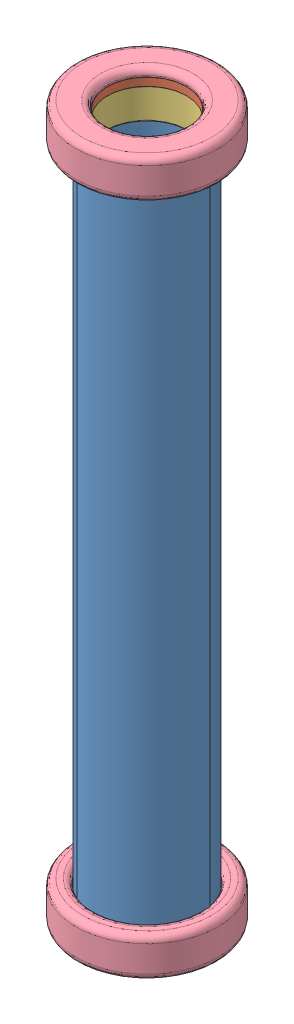
SolidWorks assembly Ftx_GeneratriceNavette, configuration Défaut. Lengths in mm.
Overall size (75.15 271 75.15).
16 component instances, 4 part files, 30 mates.
Components (placement in the parent):
- Ftx_NavetteTube-1: Ftx_NavetteTube [Défaut] at (-23.9862 -106.4594 0) size (40 265 40)
- Ftx_NavetteBague-1: Ftx_NavetteBague [Défaut] at (-23.9862 155.5406 0) size (37.5 3 37.5)
- Ftx_NavetteBague-2: Ftx_NavetteBague [Défaut] at (-23.9862 -103.4594 0) x (0.837169 0 0.546944) z (0.546944 0 -0.837169) size (37.5 3 37.5)
- Ftx_NavetteAimant-1: Ftx_NavetteAimant [Défaut] at (-23.9862 143.5406 0) size (37.5 12 37.5)
- Ftx_NavetteAimant-2: Ftx_NavetteAimant [Défaut] at (-23.9862 118.8406 0) size (37.5 12 37.5)
- Ftx_NavetteAimant-3: Ftx_NavetteAimant [Défaut] at (-23.9862 94.1406 0) size (37.5 12 37.5)
- Ftx_NavetteAimant-4: Ftx_NavetteAimant [Défaut] at (-23.9862 69.4406 0) size (37.5 12 37.5)
- Ftx_NavetteAimant-5: Ftx_NavetteAimant [Défaut] at (-23.9862 44.7406 0) size (37.5 12 37.5)
- Ftx_NavetteAimant-6: Ftx_NavetteAimant [Défaut] at (-23.9862 20.0406 0) size (37.5 12 37.5)
- Ftx_NavetteAimant-7: Ftx_NavetteAimant [Défaut] at (-23.9862 -4.6594 0) size (37.5 12 37.5)
- Ftx_NavetteAimant-8: Ftx_NavetteAimant [Défaut] at (-23.9862 -29.3594 0) size (37.5 12 37.5)
- Ftx_NavetteAimant-9: Ftx_NavetteAimant [Défaut] at (-23.9862 -54.0594 0) size (37.5 12 37.5)
- Ftx_NavetteAimant-10: Ftx_NavetteAimant [Défaut] at (-23.9862 -78.7594 0) size (37.5 12 37.5)
- Ftx_NavetteAimant-11: Ftx_NavetteAimant [Défaut] at (-23.9862 -103.4594 0) size (37.5 12 37.5)
- Ftx_NavetteButee-1: Ftx_NavetteButee [Défaut] at (-23.9862 -109.4594 0) x (0.926681 0 -0.37585) z (0.37585 0 0.926681) size (54 15 54)
- Ftx_NavetteButee-2: Ftx_NavetteButee [Défaut] at (-23.9862 161.5406 0) x (0.57022 0 0.821492) z (0.821492 0 -0.57022) size (54 15 54)
Mates (geometry in assembly coordinates):
- Coaxiale1: concentric aligned: circle of Ftx_NavetteTube-1; circle of Ftx_NavetteBague-1
- Coïncidente1: coincident aligned: plane of Ftx_NavetteTube-1 through (-23.9862 158.5406 0) normal (0 1 0); plane of Ftx_NavetteBague-1 through (-23.9862 158.5406 0) normal (0 1 0)
- Coaxiale2: concentric anti-aligned: circle of Ftx_NavetteTube-1; circle of Ftx_NavetteBague-2
- Coïncidente2: coincident aligned: plane of Ftx_NavetteTube-1 through (-23.9862 -106.4594 0) normal (0 -1 0); plane of Ftx_NavetteBague-2 through (-23.9862 -106.4594 0) normal (0 -1 0)
- Coaxiale3: concentric aligned: cylinder of Ftx_NavetteTube-1 through (-23.9862 158.5406 0) axis (0 -1 0) radius 19; cylinder of Ftx_NavetteAimant-1 through (-23.9862 155.5406 0) axis (0 -1 0) radius 18.75
- Coïncidente3: coincident anti-aligned: plane of Ftx_NavetteBague-1 through (-23.9862 155.5406 0) normal (0 -1 0); plane of Ftx_NavetteAimant-1 through (-23.9862 155.5406 0) normal (0 1 0)
- Coaxiale4: concentric aligned: cylinder of Ftx_NavetteTube-1 through (-23.9862 158.5406 0) axis (0 -1 0) radius 19; cylinder of Ftx_NavetteAimant-2 through (-23.9862 130.8406 0) axis (0 -1 0) radius 18.75
- Distance1: distance = 12.7 mm anti-aligned: plane of Ftx_NavetteAimant-2 through (-23.9862 130.8406 0) normal (0 1 0); plane of Ftx_NavetteAimant-1 through (-23.9862 143.5406 0) normal (0 -1 0)
- Coaxiale5: concentric aligned: cylinder of Ftx_NavetteTube-1 through (-23.9862 158.5406 0) axis (0 -1 0) radius 19; cylinder of Ftx_NavetteAimant-3 through (-23.9862 106.1406 0) axis (0 -1 0) radius 18.75
- Distance2: distance = 12.7 mm anti-aligned: plane of Ftx_NavetteAimant-3 through (-23.9862 106.1406 0) normal (0 1 0); plane of Ftx_NavetteAimant-2 through (-23.9862 118.8406 0) normal (0 -1 0)
- Coaxiale6: concentric aligned: cylinder of Ftx_NavetteTube-1 through (-23.9862 158.5406 0) axis (0 -1 0) radius 19; cylinder of Ftx_NavetteAimant-4 through (-23.9862 81.4406 0) axis (0 -1 0) radius 18.75
- Distance3: distance = 12.7 mm anti-aligned: plane of Ftx_NavetteAimant-4 through (-23.9862 81.4406 0) normal (0 1 0); plane of Ftx_NavetteAimant-3 through (-23.9862 94.1406 0) normal (0 -1 0)
- Coaxiale7: concentric aligned: cylinder of Ftx_NavetteTube-1 through (-23.9862 158.5406 0) axis (0 -1 0) radius 19; cylinder of Ftx_NavetteAimant-5 through (-23.9862 56.7406 0) axis (0 -1 0) radius 18.75
- Distance4: distance = 12.7 mm anti-aligned: plane of Ftx_NavetteAimant-5 through (-23.9862 56.7406 0) normal (0 1 0); plane of Ftx_NavetteAimant-4 through (-23.9862 69.4406 0) normal (0 -1 0)
- Coaxiale8: concentric aligned: cylinder of Ftx_NavetteTube-1 through (-23.9862 158.5406 0) axis (0 -1 0) radius 19; cylinder of Ftx_NavetteAimant-6 through (-23.9862 32.0406 0) axis (0 -1 0) radius 18.75
- Distance5: distance = 12.7 mm anti-aligned: plane of Ftx_NavetteAimant-6 through (-23.9862 32.0406 0) normal (0 1 0); plane of Ftx_NavetteAimant-5 through (-23.9862 44.7406 0) normal (0 -1 0)
- Coaxiale9: concentric aligned: cylinder of Ftx_NavetteTube-1 through (-23.9862 158.5406 0) axis (0 -1 0) radius 19; cylinder of Ftx_NavetteAimant-7 through (-23.9862 7.3406 0) axis (0 -1 0) radius 18.75
- Distance6: distance = 12.7 mm anti-aligned: plane of Ftx_NavetteAimant-7 through (-23.9862 7.3406 0) normal (0 1 0); plane of Ftx_NavetteAimant-6 through (-23.9862 20.0406 0) normal (0 -1 0)
- Coaxiale10: concentric aligned: cylinder of Ftx_NavetteTube-1 through (-23.9862 158.5406 0) axis (0 -1 0) radius 19; cylinder of Ftx_NavetteAimant-8 through (-23.9862 -17.3594 0) axis (0 -1 0) radius 18.75
- Distance7: distance = 12.7 mm anti-aligned: plane of Ftx_NavetteAimant-8 through (-23.9862 -17.3594 0) normal (0 1 0); plane of Ftx_NavetteAimant-7 through (-23.9862 -4.6594 0) normal (0 -1 0)
- Coaxiale11: concentric aligned: cylinder of Ftx_NavetteTube-1 through (-23.9862 158.5406 0) axis (0 -1 0) radius 19; cylinder of Ftx_NavetteAimant-9 through (-23.9862 -42.0594 0) axis (0 -1 0) radius 18.75
- Distance8: distance = 12.7 mm anti-aligned: plane of Ftx_NavetteAimant-9 through (-23.9862 -42.0594 0) normal (0 1 0); plane of Ftx_NavetteAimant-8 through (-23.9862 -29.3594 0) normal (0 -1 0)
- Coaxiale12: concentric aligned: cylinder of Ftx_NavetteTube-1 through (-23.9862 158.5406 0) axis (0 -1 0) radius 19; cylinder of Ftx_NavetteAimant-10 through (-23.9862 -66.7594 0) axis (0 -1 0) radius 18.75
- Distance9: distance = 12.7 mm anti-aligned: plane of Ftx_NavetteAimant-10 through (-23.9862 -66.7594 0) normal (0 1 0); plane of Ftx_NavetteAimant-9 through (-23.9862 -54.0594 0) normal (0 -1 0)
- Coaxiale13: concentric aligned: cylinder of Ftx_NavetteTube-1 through (-23.9862 158.5406 0) axis (0 -1 0) radius 19; cylinder of Ftx_NavetteAimant-11 through (-23.9862 -91.4594 0) axis (0 -1 0) radius 18.75
- Distance10: distance = 12.7 mm anti-aligned: plane of Ftx_NavetteAimant-11 through (-23.9862 -91.4594 0) normal (0 1 0); plane of Ftx_NavetteAimant-10 through (-23.9862 -78.7594 0) normal (0 -1 0)
- Coaxiale14: concentric anti-aligned: cylinder of Ftx_NavetteTube-1 through (-23.9862 158.5406 0) axis (0 -1 0) radius 20; cylinder of Ftx_NavetteButee-1 through (-23.9862 -106.4594 0) axis (0 1 0) radius 20
- Coïncidente4: coincident anti-aligned: plane of Ftx_NavetteBague-2 through (-23.9862 -106.4594 0) normal (0 -1 0); plane of Ftx_NavetteButee-1 through (-23.9862 -106.4594 0) normal (0 1 0)
- Coaxiale15: concentric aligned: cylinder of Ftx_NavetteTube-1 through (-23.9862 158.5406 0) axis (0 -1 0) radius 20; cylinder of Ftx_NavetteButee-2 through (-23.9862 158.5406 0) axis (0 -1 0) radius 20
- Coïncidente5: coincident anti-aligned: plane of Ftx_NavetteTube-1 through (-23.9862 158.5406 0) normal (0 1 0); plane of Ftx_NavetteButee-2 through (-23.9862 158.5406 0) normal (0 -1 0)
